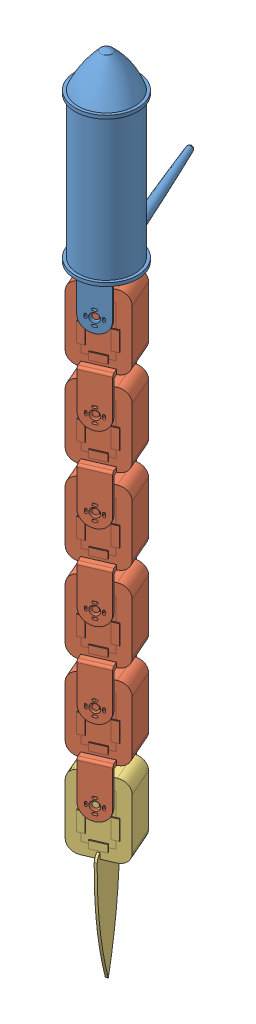
SolidWorks assembly long_tail_eel, configuration 預設. Lengths in mm.
Overall size (87.67 711.18 160.33).
7 component instances, 3 part files, 19 mates.
Components (placement in the parent):
- base_link-1: base_link [預設] at (-66.5632 -1.1579 104.9753) size (86.65 204.98 160.33)
- link2-1: link2 [預設] at (-45.8446 -161.6209 204.2877) x (0 1 0) z (0.399282 0 0.916828) size (107 45 40.5)
- link2-2: link2 [預設] at (-45.8446 -236.3209 204.2877) x (0 1 0) z (0.399282 0 0.916828) size (107 45 40.5)
- link2-3: link2 [預設] at (-45.8446 -311.0209 204.2877) x (0 1 0) z (0.399282 0 0.916828) size (107 45 40.5)
- link2-4: link2 [預設] at (-45.8446 -385.7209 204.2877) x (0 1 0) z (0.399282 0 0.916828) size (107 45 40.5)
- link2-5: link2 [預設] at (-45.8446 -460.4209 204.2877) x (0 1 0) z (0.399282 0 0.916828) size (107 45 40.5)
- long_eel-2: long_eel [預設] at (-126.787 -508.9925 59.5701) x (0 1 0) z (0.399282 0 0.916828) size (165 45 38.1)
Mates (geometry in assembly coordinates):
- 同軸心1: concentric aligned: cylinder of base_link-1 through (-52.4327 -86.9209 189.16) axis (-0.399282 0 -0.916828) radius 2.7; cylinder of link2-1 through (-51.4345 -86.9209 191.4521) axis (-0.399282 0 -0.916828) radius 2.5
- 平行1: parallel aligned: plane of base_link-1 through (-42.6286 -56.9209 181.6182) normal (0.916828 0 -0.399282); plane of link2-1 through (-19.626 -131.6209 208.1394) normal (0.916828 0 -0.399282)
- 重合/共線/共點1: coincident aligned: circle of base_link-1; plane of link2-1 through (-38.2582 -86.9209 221.7074) normal (0.399282 0 0.916828)
- 重合/共線/共點2: coincident aligned: plane of link2-1 through (-60.8832 -131.6209 226.1071) normal (-0.916828 0 0.399282); plane of link2-2 through (-60.8832 -206.3209 226.1071) normal (-0.916828 0 0.399282)
- 同軸心2: concentric anti-aligned: cylinder of link2-1 through (-53.8302 -161.6209 185.9511) axis (0.399282 0 0.916828) radius 3.7; cylinder of link2-2 through (-51.4345 -161.6209 191.4521) axis (-0.399282 0 -0.916828) radius 2.5
- 平行2: parallel aligned: plane of link2-1 through (-54.7929 -154.5209 186.3704) normal (0 -1 0); plane of link2-2 through (-54.7929 -229.2209 186.3704) normal (0 -1 0)
- 重合/共線/共點4: coincident aligned: plane of link2-1 through (-51.4345 -71.6862 191.4521) normal (-0.399282 0 -0.916828); plane of link2-2 through (-51.4345 -146.3862 191.4521) normal (-0.399282 0 -0.916828)
- 重合/共線/共點5: coincident aligned: plane of link2-2 through (-60.8832 -206.3209 226.1071) normal (-0.916828 0 0.399282); plane of link2-3 through (-60.8832 -281.0209 226.1071) normal (-0.916828 0 0.399282)
- 同軸心3: concentric anti-aligned: cylinder of link2-2 through (-53.8302 -236.3209 185.9511) axis (0.399282 0 0.916828) radius 3.7; cylinder of link2-3 through (-51.4345 -236.3209 191.4521) axis (-0.399282 0 -0.916828) radius 2.5
- 重合/共線/共點6: coincident aligned: plane of link2-2 through (-53.8302 -146.3862 185.9511) normal (-0.399282 0 -0.916828); plane of link2-3 through (-53.8302 -221.0862 185.9511) normal (-0.399282 0 -0.916828)
- 重合/共線/共點7: coincident aligned: plane of link2-3 through (-60.8832 -281.0209 226.1071) normal (-0.916828 0 0.399282); plane of link2-4 through (-60.8832 -355.7209 226.1071) normal (-0.916828 0 0.399282)
- 同軸心4: concentric anti-aligned: cylinder of link2-3 through (-53.8302 -311.0209 185.9511) axis (0.399282 0 0.916828) radius 3.7; cylinder of link2-4 through (-51.4345 -311.0209 191.4521) axis (-0.399282 0 -0.916828) radius 2.5
- 重合/共線/共點8: coincident aligned: plane of link2-3 through (-51.4345 -221.0862 191.4521) normal (-0.399282 0 -0.916828); plane of link2-4 through (-51.4345 -295.7862 191.4521) normal (-0.399282 0 -0.916828)
- 重合/共線/共點10: coincident aligned: plane of link2-4 through (-51.4345 -295.7862 191.4521) normal (-0.399282 0 -0.916828); plane of link2-5 through (-51.4345 -370.4862 191.4521) normal (-0.399282 0 -0.916828)
- 重合/共線/共點11: coincident aligned: plane of link2-4 through (-60.8832 -355.7209 226.1071) normal (-0.916828 0 0.399282); plane of link2-5 through (-60.8832 -430.4209 226.1071) normal (-0.916828 0 0.399282)
- 同軸心6: concentric anti-aligned: cylinder of link2-4 through (-53.8302 -385.7209 185.9511) axis (0.399282 0 0.916828) radius 3.7; cylinder of link2-5 through (-51.4345 -385.7209 191.4521) axis (-0.399282 0 -0.916828) radius 2.5
- 重合/共線/共點14: coincident aligned: plane of link2-5 through (-60.8832 -430.4209 226.1071) normal (-0.916828 0 0.399282); plane of long_eel-2 through (-60.8832 -505.1209 226.1071) normal (-0.916828 0 0.399282)
- 重合/共線/共點15: coincident aligned: plane of link2-5 through (-51.4345 -370.4862 191.4521) normal (-0.399282 0 -0.916828); plane of long_eel-2 through (-51.4345 -445.1862 191.4521) normal (-0.399282 0 -0.916828)
- 同軸心8: concentric aligned: cylinder of link2-5 through (-38.0586 -460.4209 222.1658) axis (-0.399282 0 -0.916828) radius 4; cylinder of long_eel-2 through (-51.4345 -460.4209 191.4521) axis (-0.399282 0 -0.916828) radius 2.5
